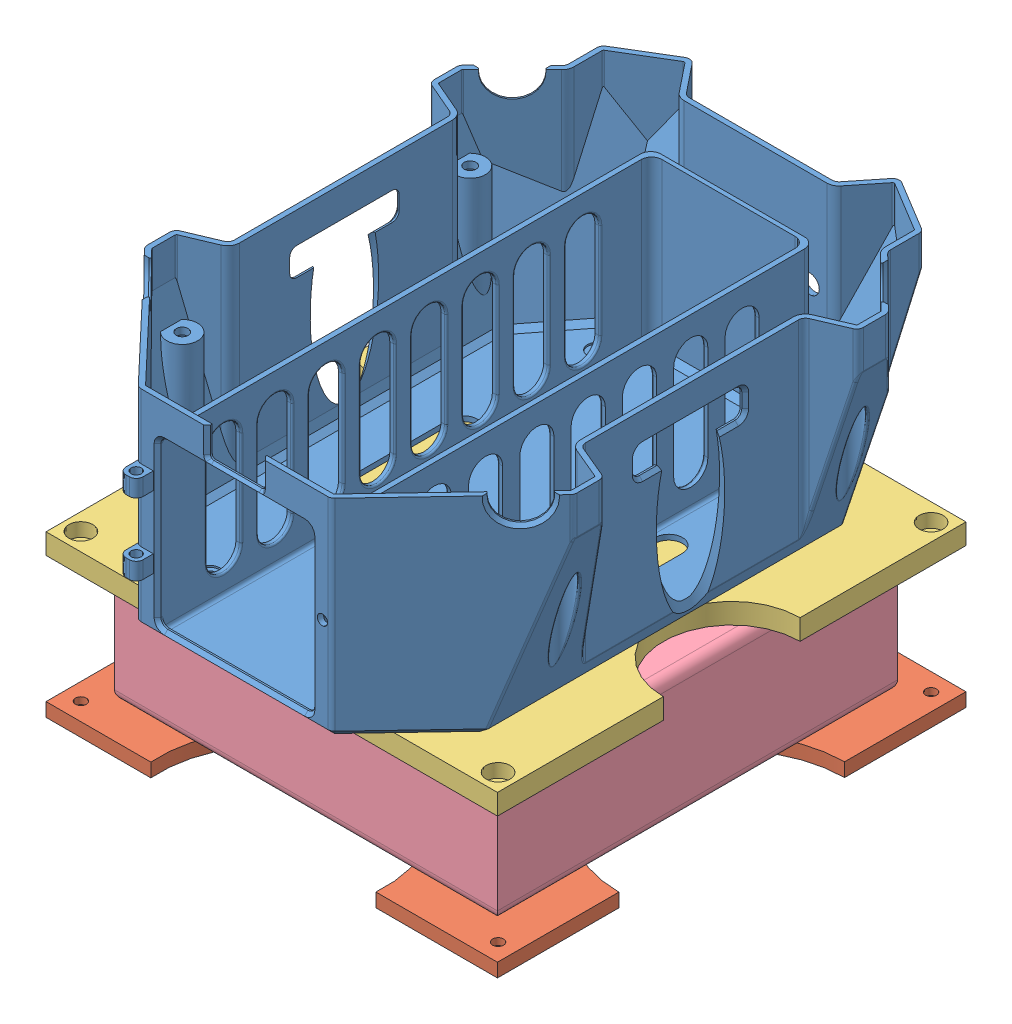
SolidWorks assembly 装配体1, configuration 默认. Lengths in mm.
Overall size (132 108.02 168.87).
4 component instances, 4 part files, 8 mates.
Components (placement in the parent):
- 底壳.stp-1: 底壳.stp [默认] at origin size (125.64 61.02 168.87)
- 零件1-1: 零件1 [默认] at (0 -104 0.0336) x (0 0 1) z (0 -1 0) size (137 132 4)
- 零件1 - 副本-1: 零件1 - 副本 [默认] at (0 -61 0.0336) x (0 0 -1) z (0 -1 0) size (137 132 6)
- 电脑-1: 电脑 [默认] at (0 -104 0.0336) x (1 0 0) z (0 1 0) size (112 117 37)
Mates (geometry in assembly coordinates):
- 重合1: coincident anti-aligned: plane of 底壳.stp-1 through (0 -61 -2.4228) normal (0 -1 0); plane of 零件1 - 副本-1 through (0 -61 0.0336) normal (0 1 0)
- 同心1: concentric anti-aligned: circle of 零件1 - 副本-1; cylinder of 底壳.stp-1 through (30 -61 56.4836) axis (0 1 0) radius 1.5
- 同心2: concentric anti-aligned: cylinder of 底壳.stp-1 through (-30 -61 56.4836) axis (0 1 0) radius 1.5; cylinder of 零件1 - 副本-1 through (-30 -63 56.4836) axis (0 -1 0) radius 4
- 重合2: coincident anti-aligned: plane of 零件1 - 副本-1 through (0 -67 0.0336) normal (0 -1 0); plane of 电脑-1 through (0 -67 0.0336) normal (0 1 0)
- 同心4: concentric anti-aligned: cylinder of 零件1 - 副本-1 through (0 -54 0.0336) axis (0 -1 0) radius 30; circle of 电脑-1
- 重合4: coincident anti-aligned: plane of 零件1-1 through (-122 -104 0.0336) normal (0 1 0); plane of 电脑-1 through (0 -104 0.0336) normal (0 -1 0)
- 同心7: concentric anti-aligned: circle of 零件1-1; circle of 零件1 - 副本-1
- 同心8: concentric aligned: circle of 零件1-1; circle of 零件1 - 副本-1
